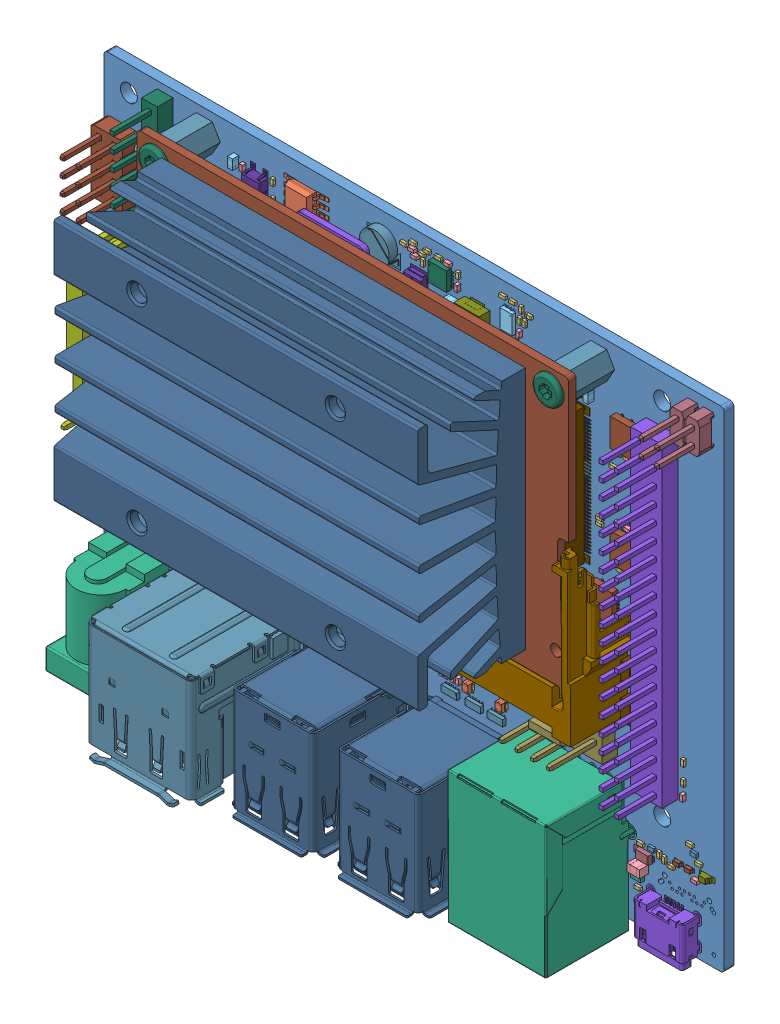
SolidWorks assembly Jetson nano_fixed, configuration Default. Lengths in mm.
Overall size (100 81.03 30.51).
401 component instances, 70 part files, 0 mates.
Components (placement in the parent):
- Jetson nano_fixed.step-1: Jetson nano_fixed.step [Default] at origin size (100 81.03 30.51)
  - 142-13449-1000-A02_ASM.step-1: 142-13449-1000-A02_ASM.step [Default] at origin size (100 81.03 23.19)
    - 142-13449-1000-A02.step-1: 142-13449-1000-A02.step [Default] at origin size (100 79 1.57)
    - 315-1109-000_1.step-1: 315-1109-000_1.step [Default] at (5.6 4.9 1.575) x (-1 0 0) z (0 0 1) size (4.5 3.5 0.8)
    - 0402_H040.step-1: 0402_H040.step [Default] at (8 -0.825 1.575) size (1 0.5 0.4)
    - 0402_H060.step-1: 0402_H060.step [Default] at (1 5 1.575) x (0 -1 0) z (0 0 1) size (1 0.5 0.6)
    - 0402_H040.step-2: 0402_H040.step [Default] at (9.9 -0.3 1.575) size (1 0.5 0.4)
    - 0402_H040.step-3: 0402_H040.step [Default] at (8.296 51.194 1.575) x (-1 0 0) z (0 0 1) size (1 0.5 0.4)
    - 0402_H040.step-4: 0402_H040.step [Default] at (76.2 36.9 1.575) x (-1 0 0) z (0 0 1) size (1 0.5 0.4)
    - 0402_H040.step-5: 0402_H040.step [Default] at (37.8 2.87 1.575) x (0 -1 0) z (0 0 1) size (1 0.5 0.4)
    - 0402_H040.step-6: 0402_H040.step [Default] at (38.6 2.87 1.575) x (0 -1 0) z (0 0 1) size (1 0.5 0.4)
    - 0402_H060.step-2: 0402_H060.step [Default] at (14.2 7.7 1.575) x (0 -1 0) z (0 0 1) size (1 0.5 0.6)
    - 0402_H040.step-7: 0402_H040.step [Default] at (64 27.5 1.575) x (-1 0 0) z (0 0 1) size (1 0.5 0.4)
    - 0402_H060.step-3: 0402_H060.step [Default] at (18.6 43.15 1.575) x (-1 0 0) z (0 0 1) size (1 0.5 0.6)
    - 0402_H060.step-4: 0402_H060.step [Default] at (65.5 52.8 1.575) x (0 1 0) z (0 0 1) size (1 0.5 0.6)
    - 0402_H060.step-5: 0402_H060.step [Default] at (64 28.4 1.575) x (-1 0 0) z (0 0 1) size (1 0.5 0.6)
    - 0402_H040.step-8: 0402_H040.step [Default] at (60.95 25.85 1.575) size (1 0.5 0.4)
    - 0402_H060.step-6: 0402_H060.step [Default] at (17.3 7.7 1.575) x (0 -1 0) z (0 0 1) size (1 0.5 0.6)
    - 0402_H060.step-7: 0402_H060.step [Default] at (18.6 7.7 1.575) x (0 -1 0) z (0 0 1) size (1 0.5 0.6)
    - 0402_H060.step-8: 0402_H060.step [Default] at (12.9 7.7 1.575) x (0 -1 0) z (0 0 1) size (1 0.5 0.6)
    - 0402_H060.step-9: 0402_H060.step [Default] at (80.9 37.7 1.575) x (-1 0 0) z (0 0 1) size (1 0.5 0.6)
    - 0402_H040.step-9: 0402_H040.step [Default] at (79.5 31.3 1.575) size (1 0.5 0.4)
    - 0402_H040.step-10: 0402_H040.step [Default] at (81 31.3 1.575) x (-1 0 0) z (0 0 1) size (1 0.5 0.4)
    - 0402_H060.step-10: 0402_H060.step [Default] at (79.3 37.7 1.575) size (1 0.5 0.6)
    - 0402_H060.step-11: 0402_H060.step [Default] at (74.8 4.05 1.575) x (-1 0 0) z (0 0 1) size (1 0.5 0.6)
    - 0402_H040.step-11: 0402_H040.step [Default] at (65.675 6.15 1.575) x (0 -1 0) z (0 0 1) size (1 0.5 0.4)
    - 0402_H060.step-12: 0402_H060.step [Default] at (67.7 6.85 1.575) x (0 1 0) z (0 0 1) size (1 0.5 0.6)
    - 0402_H040.step-12: 0402_H040.step [Default] at (64.475 5.8 1.575) x (-1 0 0) z (0 0 1) size (1 0.5 0.4)
    - 0402_H040.step-13: 0402_H040.step [Default] at (67.725 5.325 1.575) x (0 1 0) z (0 0 1) size (1 0.5 0.4)
    - 0402_H060.step-13: 0402_H060.step [Default] at (46.1 59.45 1.575) size (1 0.5 0.6)
    - 0402_H040.step-14: 0402_H040.step [Default] at (44.65 59.45 1.575) size (1 0.5 0.4)
    - 0402_H040.step-15: 0402_H040.step [Default] at (46.1 60.25 1.575) size (1 0.5 0.4)
    - 0402_H060.step-14: 0402_H060.step [Default] at (53.35 57.7 1.575) x (0 -1 0) z (0 0 1) size (1 0.5 0.6)
    - 0402_H040.step-16: 0402_H040.step [Default] at (47.6 59.45 1.575) size (1 0.5 0.4)
    - 0402_H040.step-17: 0402_H040.step [Default] at (48.4 60.25 1.575) size (1 0.5 0.4)
    - 0402_H040.step-18: 0402_H040.step [Default] at (47.7 58.325 1.575) x (0 1 0) z (0 0 1) size (1 0.5 0.4)
    - 0402_H060.step-15: 0402_H060.step [Default] at (46.5 58.65 1.575) x (-1 0 0) z (0 0 1) size (1 0.5 0.6)
    - 0402_H060.step-16: 0402_H060.step [Default] at (51.8 60.25 1.575) size (1 0.5 0.6)
    - 0402_H040.step-19: 0402_H040.step [Default] at (53.35 59.4 1.575) x (0 -1 0) z (0 0 1) size (1 0.5 0.4)
    - 0402_H040.step-20: 0402_H040.step [Default] at (50.2 60.25 1.575) x (-1 0 0) z (0 0 1) size (1 0.5 0.4)
    - 0402_H060.step-17: 0402_H060.step [Default] at (18.6 43.95 1.575) x (-1 0 0) z (0 0 1) size (1 0.5 0.6)
    - 0402_H060.step-18: 0402_H060.step [Default] at (52.75 2.9 1.575) x (0 -1 0) z (0 0 1) size (1 0.5 0.6)
    - 0402_H060.step-19: 0402_H060.step [Default] at (22.35 47.4 1.575) x (-1 0 0) z (0 0 1) size (1 0.5 0.6)
    - 0402_H060.step-20: 0402_H060.step [Default] at (20.55 47.4 1.575) x (-1 0 0) z (0 0 1) size (1 0.5 0.6)
    - 0402_H060.step-21: 0402_H060.step [Default] at (21.95 34.55 1.575) x (0 -1 0) z (0 0 1) size (1 0.5 0.6)
    - 0402_H060.step-22: 0402_H060.step [Default] at (21.05 34.55 1.575) x (0 -1 0) z (0 0 1) size (1 0.5 0.6)
    - 0402_H060.step-23: 0402_H060.step [Default] at (53.55 2.9 1.575) x (0 -1 0) z (0 0 1) size (1 0.5 0.6)
    - 0402_H060.step-24: 0402_H060.step [Default] at (25.4 54 1.575) x (-1 0 0) z (0 0 1) size (1 0.5 0.6)
    - 0402_H060.step-25: 0402_H060.step [Default] at (24 34.58 1.575) x (0 -1 0) z (0 0 1) size (1 0.5 0.6)
    - 0402_H040.step-21: 0402_H040.step [Default] at (55.6 2.95 1.575) x (0 -1 0) z (0 0 1) size (1 0.5 0.4)
    - 0402_H040.step-22: 0402_H040.step [Default] at (20.13 34.53 1.575) x (0 1 0) z (0 0 1) size (1 0.5 0.4)
    - 0402_H060.step-26: 0402_H060.step [Default] at (18.4 35.15 1.575) x (0 1 0) z (0 0 1) size (1 0.5 0.6)
    - 0402_H060.step-27: 0402_H060.step [Default] at (18.4 36.75 1.575) x (0 1 0) z (0 0 1) size (1 0.5 0.6)
    - 0402_H040.step-23: 0402_H040.step [Default] at (39.6 2.87 1.575) x (0 -1 0) z (0 0 1) size (1 0.5 0.4)
    - 0402_H040.step-24: 0402_H040.step [Default] at (40.4 2.87 1.575) x (0 -1 0) z (0 0 1) size (1 0.5 0.4)
    - 0402_H040.step-25: 0402_H040.step [Default] at (60.95 2.95 1.575) x (0 -1 0) z (0 0 1) size (1 0.5 0.4)
    - 0402_H040.step-26: 0402_H040.step [Default] at (60.15 2.95 1.575) x (0 -1 0) z (0 0 1) size (1 0.5 0.4)
    - 0402_H040.step-27: 0402_H040.step [Default] at (54.8 2.95 1.575) x (0 -1 0) z (0 0 1) size (1 0.5 0.4)
    - 0402_H040.step-28: 0402_H040.step [Default] at (31.6 54 1.575) size (1 0.5 0.4)
    - 0402_H040.step-29: 0402_H040.step [Default] at (27.4 54 1.575) size (1 0.5 0.4)
    - 0402_H040.step-30: 0402_H040.step [Default] at (29.6 54 1.575) x (-1 0 0) z (0 0 1) size (1 0.5 0.4)
    - 0402_H040.step-31: 0402_H040.step [Default] at (63.775 -14.475 1.575) size (1 0.5 0.4)
    - 0402_H040.step-32: 0402_H040.step [Default] at (63.775 -15.275 1.575) size (1 0.5 0.4)
    - 0402_H040.step-33: 0402_H040.step [Default] at (8.025 41.475 1.575) x (-1 0 0) z (0 0 1) size (1 0.5 0.4)
    - 0402_H060.step-28: 0402_H060.step [Default] at (63.95 1.25 1.575) x (0 1 0) z (0 0 1) size (1 0.5 0.6)
    - 0402_H060.step-29: 0402_H060.step [Default] at (2.95 54.05 1.575) x (0 1 0) z (0 0 1) size (1 0.5 0.6)
    - 0402_H040.step-34: 0402_H040.step [Default] at (92.2 -3.45 1.575) x (-1 0 0) z (0 0 1) size (1 0.5 0.4)
    - 0402_H060.step-30: 0402_H060.step [Default] at (32.85 7.7 1.575) x (0 -1 0) z (0 0 1) size (1 0.5 0.6)
    - 0402_H060.step-31: 0402_H060.step [Default] at (27.25 7.7 1.575) x (0 -1 0) z (0 0 1) size (1 0.5 0.6)
    - 0402_H060.step-32: 0402_H060.step [Default] at (31.25 7.7 1.575) x (0 -1 0) z (0 0 1) size (1 0.5 0.6)
    - 0402_H060.step-33: 0402_H060.step [Default] at (28.85 7.7 1.575) x (0 -1 0) z (0 0 1) size (1 0.5 0.6)
    - 0402_H060.step-34: 0402_H060.step [Default] at (32.05 7.7 1.575) x (0 -1 0) z (0 0 1) size (1 0.5 0.6)
    - 0402_H060.step-35: 0402_H060.step [Default] at (28.05 7.7 1.575) x (0 -1 0) z (0 0 1) size (1 0.5 0.6)
    - 0402_H060.step-36: 0402_H060.step [Default] at (30.45 7.7 1.575) x (0 -1 0) z (0 0 1) size (1 0.5 0.6)
    - 0402_H060.step-37: 0402_H060.step [Default] at (29.65 7.7 1.575) x (0 -1 0) z (0 0 1) size (1 0.5 0.6)
    - 0402_H060.step-38: 0402_H060.step [Default] at (24.65 6.41 1.575) x (0 -1 0) z (0 0 1) size (1 0.5 0.6)
    - 0402_H060.step-39: 0402_H060.step [Default] at (25.85 6.41 1.575) x (0 -1 0) z (0 0 1) size (1 0.5 0.6)
    - 0402_H060.step-40: 0402_H060.step [Default] at (4.2 36.5 1.575) x (0 1 0) z (0 0 1) size (1 0.5 0.6)
    - 0402_H060.step-41: 0402_H060.step [Default] at (89.7 4.7 1.575) x (0 -1 0) z (0 0 1) size (1 0.5 0.6)
    - 0402_H060.step-42: 0402_H060.step [Default] at (82.5 3.8 1.575) x (0 -1 0) z (0 0 1) size (1 0.5 0.6)
    - 0402_H060.step-43: 0402_H060.step [Default] at (12.65 49.7 1.575) size (1 0.5 0.6)
    - 0402_H060.step-44: 0402_H060.step [Default] at (11.2 50.15 1.575) x (0 -1 0) z (0 0 1) size (1 0.5 0.6)
    - 0402_H060.step-45: 0402_H060.step [Default] at (26.5 34.55 1.575) x (0 -1 0) z (0 0 1) size (1 0.5 0.6)
    - 0402_H060.step-46: 0402_H060.step [Default] at (29.9 34.5 1.575) x (0 -1 0) z (0 0 1) size (1 0.5 0.6)
    - 0402_H060.step-47: 0402_H060.step [Default] at (31.7 40.15 1.575) x (0 1 0) z (0 0 1) size (1 0.5 0.6)
    - 0402_H060.step-48: 0402_H060.step [Default] at (31.15 42.5 1.575) x (0 1 0) z (0 0 1) size (1 0.5 0.6)
    - 0402_H060.step-49: 0402_H060.step [Default] at (19.2 47.05 1.575) x (0 1 0) z (0 0 1) size (1 0.5 0.6)
    - 0402_H060.step-50: 0402_H060.step [Default] at (17.95 42 1.575) x (0 -1 0) z (0 0 1) size (1 0.5 0.6)
    - 0402_H060.step-51: 0402_H060.step [Default] at (27.3 48.25 1.575) x (0 1 0) z (0 0 1) size (1 0.5 0.6)
    - 0402_H060.step-52: 0402_H060.step [Default] at (31.7 37.85 1.575) x (0 -1 0) z (0 0 1) size (1 0.5 0.6)
    - 0402_H060.step-53: 0402_H060.step [Default] at (29.6 48.35 1.575) x (0 1 0) z (0 0 1) size (1 0.5 0.6)
    - 0402_H060.step-54: 0402_H060.step [Default] at (18.8 38.75 1.575) x (-1 0 0) z (0 0 1) size (1 0.5 0.6)
    - 0402_H060.step-55: 0402_H060.step [Default] at (18.7 57.2 1.575) x (0 -1 0) z (0 0 1) size (1 0.5 0.6)
    - 0402_H060.step-56: 0402_H060.step [Default] at (34.1 2.9 1.575) x (0 -1 0) z (0 0 1) size (1 0.5 0.6)
    - 0402_H060.step-57: 0402_H060.step [Default] at (35.8 2.9 1.575) x (0 -1 0) z (0 0 1) size (1 0.5 0.6)
    - 0402_H060.step-58: 0402_H060.step [Default] at (34.9 2.9 1.575) x (0 -1 0) z (0 0 1) size (1 0.5 0.6)
    - 0402_H060.step-59: 0402_H060.step [Default] at (36.6 2.9 1.575) x (0 -1 0) z (0 0 1) size (1 0.5 0.6)
    - 0402_H060.step-60: 0402_H060.step [Default] at (11.325 44.725 1.575) size (1 0.5 0.6)
    - 0402_H060.step-61: 0402_H060.step [Default] at (50.95 2.9 1.575) x (0 -1 0) z (0 0 1) size (1 0.5 0.6)
    - 0402_H060.step-62: 0402_H060.step [Default] at (51.75 2.9 1.575) x (0 -1 0) z (0 0 1) size (1 0.5 0.6)
    - 0402_H060.step-63: 0402_H060.step [Default] at (11.55 39.7 1.575) size (1 0.5 0.6)
    - 0402_H060.step-64: 0402_H060.step [Default] at (9.5 -8.5 1.575) x (-1 0 0) z (0 0 1) size (1 0.5 0.6)
    - 0402_H060.step-65: 0402_H060.step [Default] at (61.35 38.05 1.575) x (0 -1 0) z (0 0 1) size (1 0.5 0.6)
    - 0402_H060.step-66: 0402_H060.step [Default] at (60.55 38.05 1.575) x (0 -1 0) z (0 0 1) size (1 0.5 0.6)
    - 0402_H060.step-67: 0402_H060.step [Default] at (29.3 25.65 1.575) x (0 -1 0) z (0 0 1) size (1 0.5 0.6)
    - 0402_H060.step-68: 0402_H060.step [Default] at (63.3 56.2 1.575) x (0 1 0) z (0 0 1) size (1 0.5 0.6)
    - 0402_H060.step-69: 0402_H060.step [Default] at (20.5 54.2 1.575) size (1 0.5 0.6)
    - 0402_H060.step-70: 0402_H060.step [Default] at (60.1 32.15 1.575) x (0 1 0) z (0 0 1) size (1 0.5 0.6)
    - 0402_H060.step-71: 0402_H060.step [Default] at (60.9 32.15 1.575) x (0 1 0) z (0 0 1) size (1 0.5 0.6)
    - 0402_H060.step-72: 0402_H060.step [Default] at (18.6 44.85 1.575) size (1 0.5 0.6)
    - 0402_H060.step-73: 0402_H060.step [Default] at (18.6 45.65 1.575) size (1 0.5 0.6)
    - 0402_H060.step-74: 0402_H060.step [Default] at (18.1 27.25 1.575) size (1 0.5 0.6)
    - 0402_H060.step-75: 0402_H060.step [Default] at (15.1 7.7 1.575) x (0 -1 0) z (0 0 1) size (1 0.5 0.6)
    - 0402_H060.step-76: 0402_H060.step [Default] at (16.4 7.7 1.575) x (0 -1 0) z (0 0 1) size (1 0.5 0.6)
    - 0402_H060.step-77: 0402_H060.step [Default] at (20.8 7.7 1.575) x (0 -1 0) z (0 0 1) size (1 0.5 0.6)
    - 0402_H060.step-78: 0402_H060.step [Default] at (19.5 7.7 1.575) x (0 -1 0) z (0 0 1) size (1 0.5 0.6)
    - 0402_H060.step-79: 0402_H060.step [Default] at (21.9 2.8 1.575) size (1 0.5 0.6)
    - 0402_H060.step-80: 0402_H060.step [Default] at (12.75 29 1.575) size (1 0.5 0.6)
    - 0402_H060.step-81: 0402_H060.step [Default] at (10.225 5.1 1.575) size (1 0.5 0.6)
    - 0402_H060.step-82: 0402_H060.step [Default] at (22.8 27.65 1.575) x (0 1 0) z (0 0 1) size (1 0.5 0.6)
    - 0402_H060.step-83: 0402_H060.step [Default] at (18.85 25.15 1.575) x (0 -1 0) z (0 0 1) size (1 0.5 0.6)
    - 0402_H060.step-84: 0402_H060.step [Default] at (17.95 40.1 1.575) x (0 1 0) z (0 0 1) size (1 0.5 0.6)
    - 0402_H040.step-35: 0402_H040.step [Default] at (20.8 6.2 1.575) x (0 1 0) z (0 0 1) size (1 0.5 0.4)
    - 0402_H040.step-36: 0402_H040.step [Default] at (76 22.7 1.575) size (1 0.5 0.4)
    - 0402_H040.step-37: 0402_H040.step [Default] at (23.7 26.85 1.575) x (0 1 0) z (0 0 1) size (1 0.5 0.4)
    - 0402_H040.step-38: 0402_H040.step [Default] at (18 25.15 1.575) x (0 1 0) z (0 0 1) size (1 0.5 0.4)
    - 0402_H040.step-39: 0402_H040.step [Default] at (17.3 28.25 1.575) x (-1 0 0) z (0 0 1) size (1 0.5 0.4)
    - 0402_H040.step-40: 0402_H040.step [Default] at (13.15 4.2 1.575) x (0 -1 0) z (0 0 1) size (1 0.5 0.4)
    - 0402_H040.step-41: 0402_H040.step [Default] at (17.2 30.15 1.575) x (0 -1 0) z (0 0 1) size (1 0.5 0.4)
    - 0402_H040.step-42: 0402_H040.step [Default] at (14.2 6.2 1.575) x (0 1 0) z (0 0 1) size (1 0.5 0.4)
    - 0402_H040.step-43: 0402_H040.step [Default] at (12.9 6.2 1.575) x (0 1 0) z (0 0 1) size (1 0.5 0.4)
    - 0402_H040.step-44: 0402_H040.step [Default] at (15.1 6.2 1.575) x (0 1 0) z (0 0 1) size (1 0.5 0.4)
    - 0402_H040.step-45: 0402_H040.step [Default] at (16.4 6.2 1.575) x (0 1 0) z (0 0 1) size (1 0.5 0.4)
    - 0402_H040.step-46: 0402_H040.step [Default] at (19.5 6.2 1.575) x (0 1 0) z (0 0 1) size (1 0.5 0.4)
    - 0402_H040.step-47: 0402_H040.step [Default] at (17.3 6.2 1.575) x (0 1 0) z (0 0 1) size (1 0.5 0.4)
    - 0402_H040.step-48: 0402_H040.step [Default] at (18.6 6.2 1.575) x (0 1 0) z (0 0 1) size (1 0.5 0.4)
    - 0402_H040.step-49: 0402_H040.step [Default] at (24.2 24.55 1.575) x (0 1 0) z (0 0 1) size (1 0.5 0.4)
    - 0402_H040.step-50: 0402_H040.step [Default] at (23.5 54.9 1.575) x (0 1 0) z (0 0 1) size (1 0.5 0.4)
    - 0402_H040.step-51: 0402_H040.step [Default] at (13.2 39.75 1.575) x (-1 0 0) z (0 0 1) size (1 0.5 0.4)
    - 0402_H040.step-52: 0402_H040.step [Default] at (80.7 47.4 1.575) x (-1 0 0) z (0 0 1) size (1 0.5 0.4)
    - 0402_H040.step-53: 0402_H040.step [Default] at (77.5 22.7 1.575) x (-1 0 0) z (0 0 1) size (1 0.5 0.4)
    - 0402_H040.step-54: 0402_H040.step [Default] at (9.25 -12.75 1.575) x (-1 0 0) z (0 0 1) size (1 0.5 0.4)
    - 0402_H040.step-55: 0402_H040.step [Default] at (9.25 -11.95 1.575) x (-1 0 0) z (0 0 1) size (1 0.5 0.4)
    - 0402_H040.step-56: 0402_H040.step [Default] at (64.475 6.7 1.575) size (1 0.5 0.4)
    - 0402_H040.step-57: 0402_H040.step [Default] at (29.3 24 1.575) x (0 1 0) z (0 0 1) size (1 0.5 0.4)
    - 0402_H040.step-58: 0402_H040.step [Default] at (64.2 32.5 1.575) x (0 1 0) z (0 0 1) size (1 0.5 0.4)
    - 0402_H040.step-59: 0402_H040.step [Default] at (64.15 47.45 1.575) x (0 -1 0) z (0 0 1) size (1 0.5 0.4)
    - 0402_H040.step-60: 0402_H040.step [Default] at (64.2 31 1.575) x (0 -1 0) z (0 0 1) size (1 0.5 0.4)
    - 0402_H040.step-61: 0402_H040.step [Default] at (76.2 36.1 1.575) x (-1 0 0) z (0 0 1) size (1 0.5 0.4)
    - 0402_H040.step-62: 0402_H040.step [Default] at (78.4 45.15 1.575) size (1 0.5 0.4)
    - 0402_H040.step-63: 0402_H040.step [Default] at (81.7 38.6 1.575) size (1 0.5 0.4)
    - 0402_H040.step-64: 0402_H040.step [Default] at (81.7 39.4 1.575) size (1 0.5 0.4)
    - 0402_H040.step-65: 0402_H040.step [Default] at (59.35 51.825 1.575) size (1 0.5 0.4)
    - 0402_H040.step-66: 0402_H040.step [Default] at (60.825 51.825 1.575) x (-1 0 0) z (0 0 1) size (1 0.5 0.4)
    - 0402_H040.step-67: 0402_H040.step [Default] at (89.7 9.5 1.575) x (0 1 0) z (0 0 1) size (1 0.5 0.4)
    - 0402_H040.step-68: 0402_H040.step [Default] at (89.7 6.7 1.575) x (0 1 0) z (0 0 1) size (1 0.5 0.4)
    - 0402_H040.step-69: 0402_H040.step [Default] at (3.9 34.2 1.575) x (0 -1 0) z (0 0 1) size (1 0.5 0.4)
    - 0402_H040.step-70: 0402_H040.step [Default] at (5.1 35 1.575) x (0 1 0) z (0 0 1) size (1 0.5 0.4)
    - 0402_H040.step-71: 0402_H040.step [Default] at (32.85 5.81 1.575) x (0 -1 0) z (0 0 1) size (1 0.5 0.4)
    - 0402_H040.step-72: 0402_H040.step [Default] at (32.05 5.81 1.575) x (0 -1 0) z (0 0 1) size (1 0.5 0.4)
    - 0402_H040.step-73: 0402_H040.step [Default] at (27.25 5.81 1.575) x (0 -1 0) z (0 0 1) size (1 0.5 0.4)
    - 0402_H040.step-74: 0402_H040.step [Default] at (28.05 5.81 1.575) x (0 -1 0) z (0 0 1) size (1 0.5 0.4)
    - 0402_H040.step-75: 0402_H040.step [Default] at (31.25 5.81 1.575) x (0 -1 0) z (0 0 1) size (1 0.5 0.4)
    - 0402_H040.step-76: 0402_H040.step [Default] at (30.45 5.81 1.575) x (0 -1 0) z (0 0 1) size (1 0.5 0.4)
    - 0402_H040.step-77: 0402_H040.step [Default] at (28.85 5.81 1.575) x (0 -1 0) z (0 0 1) size (1 0.5 0.4)
    - 0402_H040.step-78: 0402_H040.step [Default] at (29.65 5.81 1.575) x (0 -1 0) z (0 0 1) size (1 0.5 0.4)
    - 0402_H040.step-79: 0402_H040.step [Default] at (13.5 52.9 1.575) x (-1 0 0) z (0 0 1) size (1 0.5 0.4)
    - 0402_H040.step-80: 0402_H040.step [Default] at (22.35 4 1.575) x (0 -1 0) z (0 0 1) size (1 0.5 0.4)
    - 0402_H040.step-81: 0402_H040.step [Default] at (21.55 4 1.575) x (0 1 0) z (0 0 1) size (1 0.5 0.4)
    - 0402_H040.step-82: 0402_H040.step [Default] at (25.85 4.9 1.575) x (0 -1 0) z (0 0 1) size (1 0.5 0.4)
    - 0402_H040.step-83: 0402_H040.step [Default] at (11.8 52.9 1.575) size (1 0.5 0.4)
    - 0402_H040.step-84: 0402_H040.step [Default] at (9.432 51.594 1.575) x (0 -1 0) z (0 0 1) size (1 0.5 0.4)
    - 0402_H040.step-85: 0402_H040.step [Default] at (8.975 50.3 1.575) size (1 0.5 0.4)
    - 0402_H040.step-86: 0402_H040.step [Default] at (82.8 -5.3 1.575) x (-1 0 0) z (0 0 1) size (1 0.5 0.4)
    - 0402_H040.step-87: 0402_H040.step [Default] at (82.4 -11.6 1.575) x (-1 0 0) z (0 0 1) size (1 0.5 0.4)
    - 0402_H040.step-88: 0402_H040.step [Default] at (22.8 26.05 1.575) x (0 1 0) z (0 0 1) size (1 0.5 0.4)
    - 0402_H040.step-89: 0402_H040.step [Default] at (20.8 28.25 1.575) size (1 0.5 0.4)
    - 0402_H040.step-90: 0402_H040.step [Default] at (20.8 24.65 1.575) x (-1 0 0) z (0 0 1) size (1 0.5 0.4)
    - 0402_H040.step-91: 0402_H040.step [Default] at (18.1 26.45 1.575) size (1 0.5 0.4)
    - 0402_H040.step-92: 0402_H040.step [Default] at (24.65 8.41 1.575) x (0 1 0) z (0 0 1) size (1 0.5 0.4)
    - 0402_H040.step-93: 0402_H040.step [Default] at (25.85 8.41 1.575) x (0 1 0) z (0 0 1) size (1 0.5 0.4)
    - 0402_H040.step-94: 0402_H040.step [Default] at (3.8 54.4 1.575) x (0 -1 0) z (0 0 1) size (1 0.5 0.4)
    - 0402_H040.step-95: 0402_H040.step [Default] at (2.45 44.45 1.575) x (0 -1 0) z (0 0 1) size (1 0.5 0.4)
    - 0402_H040.step-96: 0402_H040.step [Default] at (24.65 4.9 1.575) x (0 1 0) z (0 0 1) size (1 0.5 0.4)
    - 0402_H040.step-97: 0402_H040.step [Default] at (22.15 7.6 1.575) x (-1 0 0) z (0 0 1) size (1 0.5 0.4)
    - 0402_H040.step-98: 0402_H040.step [Default] at (79.2 47.4 1.575) size (1 0.5 0.4)
    - 0402_H040.step-99: 0402_H040.step [Default] at (19 28.25 1.575) size (1 0.5 0.4)
    - 0402_H040.step-100: 0402_H040.step [Default] at (9.65 9.7 1.575) x (0 -1 0) z (0 0 1) size (1 0.5 0.4)
    - 0402_H040.step-101: 0402_H040.step [Default] at (28.35 34.45 1.575) x (0 1 0) z (0 0 1) size (1 0.5 0.4)
    - 0402_H040.step-102: 0402_H040.step [Default] at (25.2 34.55 1.575) x (0 1 0) z (0 0 1) size (1 0.5 0.4)
    - 0402_H040.step-103: 0402_H040.step [Default] at (10.625 6.35 1.575) x (0 -1 0) z (0 0 1) size (1 0.5 0.4)
    - 0402_H040.step-104: 0402_H040.step [Default] at (9.825 6.35 1.575) x (0 1 0) z (0 0 1) size (1 0.5 0.4)
    - 0402_H040.step-105: 0402_H040.step [Default] at (4.775 42.975 1.575) x (0 1 0) z (0 0 1) size (1 0.5 0.4)
    - 0402_H040.step-106: 0402_H040.step [Default] at (19.8 32.9 1.575) x (-1 0 0) z (0 0 1) size (1 0.5 0.4)
    - 0402_H040.step-107: 0402_H040.step [Default] at (22.35 24.65 1.575) x (-1 0 0) z (0 0 1) size (1 0.5 0.4)
    - 0402_H040.step-108: 0402_H040.step [Default] at (62.4 54.7 1.575) size (1 0.5 0.4)
    - 0402_H040.step-109: 0402_H040.step [Default] at (62.2 60.05 1.575) x (-1 0 0) z (0 0 1) size (1 0.5 0.4)
    - 0402_H040.step-110: 0402_H040.step [Default] at (23.5 57.5 1.575) x (0 1 0) z (0 0 1) size (1 0.5 0.4)
    - 0402_H040.step-111: 0402_H040.step [Default] at (12.8 44.725 1.575) size (1 0.5 0.4)
    - 0402_H040.step-112: 0402_H040.step [Default] at (21.8 31.45 1.575) x (0 1 0) z (0 0 1) size (1 0.5 0.4)
    - 0402_H040.step-113: 0402_H040.step [Default] at (19.25 34.55 1.575) x (0 1 0) z (0 0 1) size (1 0.5 0.4)
    - 0402_H040.step-114: 0402_H040.step [Default] at (0.95 41.55 1.575) size (1 0.5 0.4)
    - 0402_H040.step-115: 0402_H040.step [Default] at (64.1 58 1.575) x (0 1 0) z (0 0 1) size (1 0.5 0.4)
    - 0402_H040.step-116: 0402_H040.step [Default] at (63.3 58 1.575) x (0 -1 0) z (0 0 1) size (1 0.5 0.4)
    - 0402_H040.step-117: 0402_H040.step [Default] at (63.55 59.7 1.575) x (0 -1 0) z (0 0 1) size (1 0.5 0.4)
    - 0402_H060.step-85: 0402_H060.step [Default] at (71.175 4 1.575) x (-1 0 0) z (0 0 1) size (1 0.5 0.6)
    - 0402_H040.step-118: 0402_H040.step [Default] at (86.6 -5.6 1.575) x (0 1 0) z (0 0 1) size (1 0.5 0.4)
    - 0402_H040.step-119: 0402_H040.step [Default] at (85.8 -5.3 1.575) x (0 1 0) z (0 0 1) size (1 0.5 0.4)
    - 0402_H040.step-120: 0402_H040.step [Default] at (10.25 51.6 1.575) x (0 1 0) z (0 0 1) size (1 0.5 0.4)
    - 0402_H040.step-121: 0402_H040.step [Default] at (80.5 28.55 1.575) size (1 0.5 0.4)
    - 0402_H040.step-122: 0402_H040.step [Default] at (13.95 4.2 1.575) x (0 -1 0) z (0 0 1) size (1 0.5 0.4)
    - 0402_H040.step-123: 0402_H040.step [Default] at (15.35 4.2 1.575) x (0 -1 0) z (0 0 1) size (1 0.5 0.4)
    - 0402_H040.step-124: 0402_H040.step [Default] at (16.15 4.2 1.575) x (0 -1 0) z (0 0 1) size (1 0.5 0.4)
    - 0402_H040.step-125: 0402_H040.step [Default] at (20.55 4.2 1.575) x (0 -1 0) z (0 0 1) size (1 0.5 0.4)
    - 0402_H040.step-126: 0402_H040.step [Default] at (19.75 4.2 1.575) x (0 -1 0) z (0 0 1) size (1 0.5 0.4)
    - 0402_H040.step-127: 0402_H040.step [Default] at (17.6 4.2 1.575) x (0 -1 0) z (0 0 1) size (1 0.5 0.4)
    - 0402_H040.step-128: 0402_H040.step [Default] at (18.4 4.2 1.575) x (0 -1 0) z (0 0 1) size (1 0.5 0.4)
    - 0402_H060.step-86: 0402_H060.step [Default] at (64.25 -13.325 1.575) x (0 -1 0) z (0 0 1) size (1 0.5 0.6)
    - 0402_H060.step-87: 0402_H060.step [Default] at (64.225 -11.825 1.575) x (0 1 0) z (0 0 1) size (1 0.5 0.6)
    - 0402_H040.step-129: 0402_H040.step [Default] at (63.8 -6.85 1.575) x (0 1 0) z (0 0 1) size (1 0.5 0.4)
    - 0402_H040.step-130: 0402_H040.step [Default] at (81.7 41.95 1.575) size (1 0.5 0.4)
    - 0402_H040.step-131: 0402_H040.step [Default] at (87.75 -6 1.575) x (-1 0 0) z (0 0 1) size (1 0.5 0.4)
    - 0402_H040.step-132: 0402_H040.step [Default] at (82.4 -13.6 1.575) x (-1 0 0) z (0 0 1) size (1 0.5 0.4)
    - 0402_H060.step-88: 0402_H060.step [Default] at (91.75 -5.95 1.575) size (1 0.5 0.6)
    - 0402_H040.step-133: 0402_H040.step [Default] at (3.65 49.25 1.575) x (0 -1 0) z (0 0 1) size (1 0.5 0.4)
    - 0402_H040.step-134: 0402_H040.step [Default] at (2.45 49.25 1.575) x (0 1 0) z (0 0 1) size (1 0.5 0.4)
    - 0402_H040.step-135: 0402_H040.step [Default] at (90.75 -1.45 1.575) x (-1 0 0) z (0 0 1) size (1 0.5 0.4)
    - 0402_H040.step-136: 0402_H040.step [Default] at (8.45 39.55 1.575) x (0 -1 0) z (0 0 1) size (1 0.5 0.4)
    - 0402_H060.step-89: 0402_H060.step [Default] at (8.85 -5.25 1.575) x (-1 0 0) z (0 0 1) size (1 0.5 0.6)
    - 0402_H040.step-137: 0402_H040.step [Default] at (18.6 32.55 1.575) x (0 1 0) z (0 0 1) size (1 0.5 0.4)
    - 0402_H060.step-90: 0402_H060.step [Default] at (4.5 44.45 1.575) x (0 1 0) z (0 0 1) size (1 0.5 0.6)
    - 0402_H040.step-138: 0402_H040.step [Default] at (8.35 2.75 1.575) size (1 0.5 0.4)
    - 0402_H040.step-139: 0402_H040.step [Default] at (9.4 1.95 1.575) size (1 0.5 0.4)
    - 0402_H040.step-140: 0402_H040.step [Default] at (8.2 1.55 1.575) x (0 1 0) z (0 0 1) size (1 0.5 0.4)
    - 0402_H060.step-91: 0402_H060.step [Default] at (8.5 3.875 1.575) x (0 -1 0) z (0 0 1) size (1 0.5 0.6)
    - 0402_H060.step-92: 0402_H060.step [Default] at (-0.8 41.5 1.575) x (-1 0 0) z (0 0 1) size (1 0.5 0.6)
    - 0402_H040.step-141: 0402_H040.step [Default] at (-1.35 7.75 1.575) size (1 0.5 0.4)
    - 0402_H040.step-142: 0402_H040.step [Default] at (8 0.425 1.575) size (1 0.5 0.4)
    - 0402_H040.step-143: 0402_H040.step [Default] at (67.9 4.025 1.575) x (-1 0 0) z (0 0 1) size (1 0.5 0.4)
    - 0402_H040.step-144: 0402_H040.step [Default] at (60.6 60.05 1.575) x (-1 0 0) z (0 0 1) size (1 0.5 0.4)
    - 0402_H040.step-145: 0402_H040.step [Default] at (72.85 4 1.575) x (-1 0 0) z (0 0 1) size (1 0.5 0.4)
    - 0402_H040.step-146: 0402_H040.step [Default] at (64.8 59.35 1.575) size (1 0.5 0.4)
    - 0402_H040.step-147: 0402_H040.step [Default] at (7.2 7.3 1.575) size (1 0.5 0.4)
    - 0402_H040.step-148: 0402_H040.step [Default] at (8.5 5.35 1.575) x (0 1 0) z (0 0 1) size (1 0.5 0.4)
    - 0402_H040.step-149: 0402_H040.step [Default] at (8.475 7.075 1.575) x (0 1 0) z (0 0 1) size (1 0.5 0.4)
    - VIRTUAL_SHORT.step-1: VIRTUAL_SHORT.step [Default] at (23.5 32.9 1.575) x (0 1 0) z (0 0 1) size (0.25 0.25 1)
    - VIRTUAL_SHORT.step-2: VIRTUAL_SHORT.step [Default] at (26.85 32.85 1.575) x (0 1 0) z (0 0 1) size (0.25 0.25 1)
    - VIRTUAL_SHORT.step-3: VIRTUAL_SHORT.step [Default] at (30.6 33.8 1.575) x (0 1 0) z (0 0 1) size (0.25 0.25 1)
    - VIRTUAL_SHORT.step-4: VIRTUAL_SHORT.step [Default] at (32.65 39.75 1.575) x (-1 0 0) z (0 0 1) size (0.25 0.25 1)
    - VIRTUAL_SHORT.step-5: VIRTUAL_SHORT.step [Default] at (31.85 42.1 1.575) x (-1 0 0) z (0 0 1) size (0.25 0.25 1)
    - VIRTUAL_SHORT.step-6: VIRTUAL_SHORT.step [Default] at (17.35 42.4 1.575) size (0.25 0.25 1)
    - VIRTUAL_SHORT.step-7: VIRTUAL_SHORT.step [Default] at (18.6 46.6 1.575) size (0.25 0.25 1)
    - VIRTUAL_SHORT.step-8: VIRTUAL_SHORT.step [Default] at (20.9 32.9 1.575) x (0 1 0) z (0 0 1) size (0.25 0.25 1)
    - VIRTUAL_SHORT.step-9: VIRTUAL_SHORT.step [Default] at (28.6 48.25 1.575) x (0 -1 0) z (0 0 1) size (0.25 0.25 1)
    - VIRTUAL_SHORT.step-10: VIRTUAL_SHORT.step [Default] at (27.1 49.35 1.575) x (0 -1 0) z (0 0 1) size (0.25 0.25 1)
    - VIRTUAL_SHORT.step-11: VIRTUAL_SHORT.step [Default] at (22.1 32.95 1.575) x (-1 0 0) z (0 0 1) size (0.25 0.25 1)
    - VIRTUAL_SHORT.step-12: VIRTUAL_SHORT.step [Default] at (32.65 38.25 1.575) x (-1 0 0) z (0 0 1) size (0.25 0.25 1)
    - VIRTUAL_SHORT.step-13: VIRTUAL_SHORT.step [Default] at (30.3 48 1.575) x (-1 0 0) z (0 0 1) size (0.25 0.25 1)
    - VIRTUAL_SHORT.step-14: VIRTUAL_SHORT.step [Default] at (17.15 38.95 1.575) size (0.25 0.25 1)
    - VIRTUAL_SHORT.step-15: VIRTUAL_SHORT.step [Default] at (17.15 39.7 1.575) size (0.25 0.25 1)
    - VIRTUAL_SHORT.step-16: VIRTUAL_SHORT.step [Default] at (76.175 4.1 1.575) x (-1 0 0) z (0 0 1) size (0.25 0.25 1)
    - 064-0377-000_2.step-1: 064-0377-000_2.step [Default] at (2 -4.75 1.575) x (0 -1 0) z (0 0 1) size (14.63 10.08 14.5)
    - 074-0117-000_2.step-1: 074-0117-000_2.step [Default] at (0.254 14.3 1.575) size (5.08 2.54 11.66)
    - 090-0096-000_1.step-1: 090-0096-000_1.step [Default] at (3.45 44.4 1.575) x (0 -1 0) z (0 0 1) size (1.2 0.6 0.4)
    - 090-0309-000_1.step-1: 090-0309-000_1.step [Default] at (-1.65 8.7 1.575) x (-1 0 0) z (0 0 1) size (1.2 0.6 0.4)
    - 115-1232-000_2.step-1: 115-1232-000_2.step [Default] at (1.25 6.5 1.575) x (-1 0 0) z (0 0 1) size (0.9 0.9 0.33)
    - 074-0102-000_4.step-1: 074-0102-000_4.step [Default] at (0.254 44.36 1.575) x (0 1 0) z (0 0 1) size (10.16 5.08 11.6)
    - 064-0400-000_1.step-1: 064-0400-000_1.step [Default] at (73.75 7.77 1.575) size (10.16 5.8 13.5)
    - MEC_STANDOFF_PTH_620C380P.step-1: MEC_STANDOFF_PTH_620C380P.step [Default] at (40.276 40.3 1.575) x (0 1 0) z (0 0 1) size (6.2 6.2 0.73)
    - 090-0231-000_1.step-1: 090-0231-000_1.step [Default] at (35.3 0.7 1.575) x (-1 0 0) z (0 0 1) size (2.5 1.55 0.55)
    - 090-0231-000_1.step-2: 090-0231-000_1.step [Default] at (52.25 0.7 1.575) x (-1 0 0) z (0 0 1) size (2.5 1.55 0.55)
    - 090-0231-000_1.step-3: 090-0231-000_1.step [Default] at (56.05 0.7 1.575) size (2.5 1.55 0.55)
    - 090-0231-000_1.step-4: 090-0231-000_1.step [Default] at (59.65 0.7 1.575) size (2.5 1.55 0.55)
    - 090-0231-000_1.step-5: 090-0231-000_1.step [Default] at (39.1 0.7 1.575) size (2.5 1.55 0.55)
    - 090-0231-000_1.step-6: 090-0231-000_1.step [Default] at (43.1 0.7 1.575) size (2.5 1.55 0.55)
    - 090-0231-000_1.step-7: 090-0231-000_1.step [Default] at (14.6 1.8 1.575) size (2.5 1.55 0.55)
    - 090-0231-000_1.step-8: 090-0231-000_1.step [Default] at (19.1 1.8 1.575) size (2.5 1.55 0.55)
    - 090-0231-000_1.step-9: 090-0231-000_1.step [Default] at (22.5 1.4 1.575) size (2.5 1.55 0.55)
    - 090-0231-000_1.step-10: 090-0231-000_1.step [Default] at (28.45 3.35 1.575) size (2.5 1.55 0.55)
    - 090-0231-000_1.step-11: 090-0231-000_1.step [Default] at (31.65 3.35 1.575) size (2.5 1.55 0.55)
    - 074-0223-000_2.step-1: 074-0223-000_2.step [Default] at (5.85 53.25 1.575) x (0 1 0) z (0 0 1) size (15.24 2.54 11.6)
    - 131-0832-000_2.step-1: 131-0832-000_2.step [Default] at (56.3 54.7 1.575) x (0 -1 0) z (0 0 1) size (4.96 4.06 1.8)
    - 115-0836-000_1.step-1: 115-0836-000_1.step [Default] at (21.1 56.6 1.575) size (2.9 3.58 1.45)
    - 115-0836-000_1.step-2: 115-0836-000_1.step [Default] at (11.8 42.3 1.575) size (2.9 3.58 1.45)
    - 315-0620-000_1.step-1: 315-0620-000_1.step [Default] at (72.1 53.4 1.575) x (0 -1 0) z (0 0 1) size (2.9 3.58 1.1)
    - 315-1062-000_1.step-1: 315-1062-000_1.step [Default] at (26.8 25.15 1.575) x (0 -1 0) z (0 0 1) size (2.9 3.58 1.45)
    - 170-0285-000_1.step-1: 170-0285-000_1.step [Default] at (28.72 57.28 1.575) x (0 1 0) z (0 0 1) size (4.9 7.21 1.75)
    - 115-0138-000_1.step-1: 115-0138-000_1.step [Default] at (9.15 48.55 1.575) x (0 1 0) z (0 0 1) size (2 2.88 1.1)
    - 115-1821-000_1.step-1: 115-1821-000_1.step [Default] at (3.3 40.8 1.575) x (-1 0 0) z (0 0 1) size (2 2.88 1.1)
    - 115-1821-000_1.step-2: 115-1821-000_1.step [Default] at (6.25 39.55 1.575) x (0 -1 0) z (0 0 1) size (2 2.88 1.1)
    - 115-0742-000_2.step-1: 115-0742-000_2.step [Default] at (3.05 46.85 1.575) size (2 2.88 1.1)
    - 115-0742-000_2.step-2: 115-0742-000_2.step [Default] at (3.05 51.65 1.575) x (-1 0 0) z (0 0 1) size (2 2.88 1.1)
    - 115-1821-000_1.step-3: 115-1821-000_1.step [Default] at (59.6 27.6 1.575) x (0 1 0) z (0 0 1) size (2 2.88 1.1)
    - 091-0022-000_1.step-1: 091-0022-000_1.step [Default] at (-0.95 5.7 1.575) size (2 2.51 1.1)
    - 091-0023-000_1.step-1: 091-0023-000_1.step [Default] at (15.25 29.9 1.575) x (0 -1 0) z (0 0 1) size (2 2.51 1.1)
    - 080-1368-000_1.step-1: 080-1368-000_1.step [Default] at (88 -14.3 1.575) size (10.99 7.28 4.95)
    - 080-1656-000_3.step-1: 080-1656-000_3.step [Default] at (44 16.6 1.575) x (-1 0 0) z (0 0 1) size (77.5 25.85 9.76)
    - 090-0243-000_1.step-1: 090-0243-000_1.step [Default] at (8.5 -4.1 1.575) x (-1 0 0) z (0 0 1) size (1.41 0.61 0.45)
    - 090-0243-000_1.step-2: 090-0243-000_1.step [Default] at (9.95 -3.7 1.575) x (0 1 0) z (0 0 1) size (1.41 0.61 0.45)
    - 090-0243-000_1.step-3: 090-0243-000_1.step [Default] at (9.5 -10.95 1.575) x (-1 0 0) z (0 0 1) size (1.41 0.61 0.45)
    - 090-0243-000_1.step-4: 090-0243-000_1.step [Default] at (9.8 -6.25 1.575) x (-1 0 0) z (0 0 1) size (1.41 0.61 0.45)
    - 090-0243-000_1.step-5: 090-0243-000_1.step [Default] at (9.5 -9.5 1.575) x (-1 0 0) z (0 0 1) size (1.41 0.61 0.45)
    - 090-0172-000_1.step-1: 090-0172-000_1.step [Default] at (90.6 -5 1.575) size (1.41 0.61 0.55)
    - 090-0172-000_1.step-2: 090-0172-000_1.step [Default] at (88.8 -5 1.575) x (-1 0 0) z (0 0 1) size (1.41 0.61 0.55)
    - 115-2177-000_2.step-1: 115-2177-000_2.step [Default] at (12.7 51.35 1.575) x (0 1 0) z (0 0 1) size (1.8 1.71 0.4)
    - 090-0233-000_1.step-1: 090-0233-000_1.step [Default] at (83.5 -6.6 1.575) size (3.3 1.3 0.74)
    - 064-0374-000_2.step-1: 064-0374-000_2.step [Default] at (19.75 -9.65 1.575) size (18.11 18.56 21.86)
    - 115-2628-000_3.step-1: 115-2628-000_3.step [Default] at (25.2 41.2 1.575) size (9.5 9.5 0.9)
    - 092-0073-000_1.step-1: 092-0073-000_1.step [Default] at (93.35 -4.75 1.575) x (-1 0 0) z (0 0 1) size (2.46 0.81 0.9)
    - IND_SMD_0402_H060.step-1: IND_SMD_0402_H060.step [Default] at (12.85 29.9 1.575) x (-1 0 0) z (0 0 1) size (1 0.5 0.6)
    - 1206_H190.step-1: 1206_H190.step [Default] at (82 18.8 1.575) x (0 1 0) z (0 0 1) size (3.2 1.6 1.9)
    - 1206_H190.step-2: 1206_H190.step [Default] at (81.95 13.5 1.575) x (0 -1 0) z (0 0 1) size (3.2 1.6 1.9)
    - 300-0868-000_3.step-1: 300-0868-000_3.step [Default] at (69.6 4 1.575) x (-1 0 0) z (0 0 1) size (1 0.6 0.4)
    - 300-0868-000_3.step-2: 300-0868-000_3.step [Default] at (9.55 0.95 1.575) size (1 0.6 0.4)
    - 300-0868-000_3.step-3: 300-0868-000_3.step [Default] at (19.6 31.45 1.575) x (0 -1 0) z (0 0 1) size (1 0.6 0.4)
    - 300-0868-000_3.step-4: 300-0868-000_3.step [Default] at (91.45 -2.45 1.575) x (-1 0 0) z (0 0 1) size (1 0.6 0.4)
    - 300-0868-000_3.step-5: 300-0868-000_3.step [Default] at (84.6 -5.1 1.575) size (1 0.6 0.4)
    - 300-0868-000_3.step-6: 300-0868-000_3.step [Default] at (66.725 5.875 1.575) x (0 -1 0) z (0 0 1) size (1 0.6 0.4)
    - 300-0868-000_3.step-7: 300-0868-000_3.step [Default] at (20.8 31.45 1.575) x (0 -1 0) z (0 0 1) size (1 0.6 0.4)
    - 300-0868-000_3.step-8: 300-0868-000_3.step [Default] at (62.9 31.35 1.575) x (-1 0 0) z (0 0 1) size (1 0.6 0.4)
    - 300-0868-000_3.step-9: 300-0868-000_3.step [Default] at (65.475 4.8 1.575) x (-1 0 0) z (0 0 1) size (1 0.6 0.4)
    - 300-0868-000_3.step-10: 300-0868-000_3.step [Default] at (63.9 33.85 1.575) x (-1 0 0) z (0 0 1) size (1 0.6 0.4)
    - 300-0868-000_3.step-11: 300-0868-000_3.step [Default] at (15.65 27.9 1.575) size (1 0.6 0.4)
    - 300-0868-000_3.step-12: 300-0868-000_3.step [Default] at (11.8 6.1 1.575) x (0 1 0) z (0 0 1) size (1 0.6 0.4)
    - 300-0868-000_3.step-13: 300-0868-000_3.step [Default] at (22.1 6.25 1.575) x (0 1 0) z (0 0 1) size (1 0.6 0.4)
    - 300-0869-000_3.step-1: 300-0869-000_3.step [Default] at (9.65 8.1 1.575) x (0 -1 0) z (0 0 1) size (1 0.6 0.53)
    - 300-0402-000_1.step-1: 300-0402-000_1.step [Default] at (20.8 26.45 1.575) x (0 -1 0) z (0 0 1) size (2 2.69 1.1)
    - 300-0560-000_1.step-1: 300-0560-000_1.step [Default] at (6.8 43.65 1.575) x (-1 0 0) z (0 0 1) size (2 2.69 1.1)
    - 174-0159-000_2.step-1: 174-0159-000_2.step [Default] at (61.49 57.15 1.575) x (-1 0 0) z (0 0 1) size (2 3.52 0.6)
    - 064-0373-000_2.step-1: 064-0373-000_2.step [Default] at (72.95 -7.825 1.575) size (17.8 21.61 17.46)
    - 064-0375-000_2.step-1: 064-0375-000_2.step [Default] at (19.751 -12.275 1.575) size (16.2 5.58 0.01)
    - 074-0221-000_3.step-1: 074-0221-000_3.step [Default] at (86 29 1.575) x (0 1 0) z (0 0 1) size (50.8 5.08 11.6)
    - 2016MM_H100.step-1: 2016MM_H100.step [Default] at (24.5 49.25 1.575) x (0 1 0) z (0 0 1) size (2 1.6 1)
    - 065-0656-000_2.step-1: 065-0656-000_2.step [Default] at (55.6 -10.04 1.575) x (-1 0 0) z (0 0 1) size (16.19 17.45 19.62)
    - 065-0656-000_2.step-2: 065-0656-000_2.step [Default] at (38.6 -10.04 1.575) x (-1 0 0) z (0 0 1) size (16.19 17.45 19.62)
    - 115-1921-000_3.step-1: 115-1921-000_3.step [Default] at (80.45 50.52 1.575) x (0 -1 0) z (0 0 1) size (5 4 1)
    - 115-1921-000_3.step-2: 115-1921-000_3.step [Default] at (80.4 34.5 1.575) x (0 -1 0) z (0 0 1) size (5 4 1)
    - 115-1921-000_3.step-3: 115-1921-000_3.step [Default] at (77.2 25.9 1.575) x (0 -1 0) z (0 0 1) size (5 4 1)
    - 085-0328-000_2.step-1: 085-0328-000_2.step [Default] at (16.28 36.32 1.575) x (0 -1 0) z (0 0 1) size (3.81 2.5 0.6)
    - 074-0216-000_2.step-1: 074-0216-000_2.step [Default] at (92.14 58 1.575) x (-1 0 0) z (0 0 1) size (4.83 5 11.5)
    - 060-0002-000_1.step-1: 060-0002-000_1.step [Default] at (41.2 57.9 1.575) x (0 -1 0) z (0 0 1) size (5.1 5.4 1.68)
    - 316-0697-000_1.step-1: 316-0697-000_1.step [Default] at (50.6 58.1 1.575) x (0 -1 0) z (0 0 1) size (3 3.72 0.8)
    - 032-0256-000_1.step-1: 032-0256-000_1.step [Default] at (5.925 9.425 1.575) size (4.22 2.82 2)
    - 041-0092-000_1.step-1: 041-0092-000_1.step [Default] at (46.9 54.9 1.575) x (0 -1 0) z (0 0 1) size (4.22 2.82 1.2)
    - 080-1243-000_3.step-1: 080-1243-000_3.step [Default] at (69.9 40.3 1.575) x (0 -1 0) z (0 0 1) size (21.9 9.1 4.8)
    - 102-0066-000_2.step-1: 102-0066-000_2.step [Default] at (18 4.2 1.575) size (1 1.86 0.61)
    - 102-0066-000_2.step-2: 102-0066-000_2.step [Default] at (13.55 4.2 1.575) size (1 1.86 0.61)
    - 102-0066-000_2.step-3: 102-0066-000_2.step [Default] at (32.45 5.81 1.575) size (1 1.86 0.61)
    - 102-0066-000_2.step-4: 102-0066-000_2.step [Default] at (27.65 5.81 1.575) size (1 1.86 0.61)
    - 102-0066-000_2.step-5: 102-0066-000_2.step [Default] at (20.15 4.2 1.575) size (1 1.86 0.61)
    - 102-0066-000_2.step-6: 102-0066-000_2.step [Default] at (15.75 4.2 1.575) size (1 1.86 0.61)
    - 102-0066-000_2.step-7: 102-0066-000_2.step [Default] at (29.25 5.81 1.575) size (1 1.86 0.61)
    - 102-0066-000_2.step-8: 102-0066-000_2.step [Default] at (30.85 5.81 1.575) size (1 1.86 0.61)
    - 102-0037-000_1.step-1: 102-0037-000_1.step [Default] at (55.2 2.95 1.575) x (-1 0 0) z (0 0 1) size (1 1.86 0.91)
    - 102-0037-000_1.step-2: 102-0037-000_1.step [Default] at (39.99 2.87 1.575) x (-1 0 0) z (0 0 1) size (1 1.86 0.91)
    - 102-0037-000_1.step-3: 102-0037-000_1.step [Default] at (60.55 2.95 1.575) x (-1 0 0) z (0 0 1) size (1 1.86 0.91)
    - 102-0037-000_1.step-4: 102-0037-000_1.step [Default] at (38.22 2.87 1.575) x (-1 0 0) z (0 0 1) size (1 1.86 0.91)
    - 0805_H140.step-1: 0805_H140.step [Default] at (8.1 -2.1 1.575) size (2.01 1.25 1.4)
    - 0805_H150.step-1: 0805_H150.step [Default] at (82.9 -8.4 1.575) x (-1 0 0) z (0 0 1) size (2.01 1.25 1.5)
    - 0603_H100.step-1: 0603_H100.step [Default] at (6.1 41.525 1.575) x (-1 0 0) z (0 0 1) size (1.6 0.81 1)
    - 0603_H060.step-1: 0603_H060.step [Default] at (63.25 -12 1.575) x (0 1 0) z (0 0 1) size (1.6 0.81 0.6)
    - 0603_H060.step-2: 0603_H060.step [Default] at (63.8 -0.7 1.575) x (0 -1 0) z (0 0 1) size (1.6 0.81 0.6)
    - 0603_H060.step-3: 0603_H060.step [Default] at (82.4 -10 1.575) x (-1 0 0) z (0 0 1) size (1.6 0.81 0.6)
    - 0603_H100.step-2: 0603_H100.step [Default] at (9.486 -7.5 1.575) x (-1 0 0) z (0 0 1) size (1.6 0.81 1)
    - 0603_H100.step-3: 0603_H100.step [Default] at (17.4 57.4 1.575) x (0 -1 0) z (0 0 1) size (1.6 0.81 1)
    - 0603_H100.step-4: 0603_H100.step [Default] at (30.35 25.9 1.575) x (0 -1 0) z (0 0 1) size (1.6 0.81 1)
    - 0603_H100.step-5: 0603_H100.step [Default] at (11.4 45.7 1.575) size (1.6 0.81 1)
    - 0603_H100.step-6: 0603_H100.step [Default] at (3.2 43 1.575) size (1.6 0.81 1)
    - 0603_H100.step-7: 0603_H100.step [Default] at (74.7 53.4 1.575) x (0 -1 0) z (0 0 1) size (1.6 0.81 1)
    - 0603_H100.step-8: 0603_H100.step [Default] at (69.5 53.9 1.575) x (0 -1 0) z (0 0 1) size (1.6 0.81 1)
    - 0603_H100.step-9: 0603_H100.step [Default] at (52.5 52.9 1.575) x (-1 0 0) z (0 0 1) size (1.6 0.81 1)
    - 0603_H100.step-10: 0603_H100.step [Default] at (52.5 54.2 1.575) x (-1 0 0) z (0 0 1) size (1.6 0.81 1)
    - 0603_H100.step-11: 0603_H100.step [Default] at (27.3 51.35 1.575) size (1.6 0.81 1)
    - 0603_H100.step-12: 0603_H100.step [Default] at (22.7 49.1 1.575) x (0 1 0) z (0 0 1) size (1.6 0.81 1)
    - 0603_H100.step-13: 0603_H100.step [Default] at (26.2 48.8 1.575) x (0 1 0) z (0 0 1) size (1.6 0.81 1)
    - 0603_H100.step-14: 0603_H100.step [Default] at (20.9 49.1 1.575) x (0 1 0) z (0 0 1) size (1.6 0.81 1)
    - 0603_H100.step-15: 0603_H100.step [Default] at (65.5 27.4 1.575) x (0 -1 0) z (0 0 1) size (1.6 0.81 1)
    - 0603_H100.step-16: 0603_H100.step [Default] at (63.8 52.2 1.575) x (-1 0 0) z (0 0 1) size (1.6 0.81 1)
    - 0603_H100.step-17: 0603_H100.step [Default] at (52.5 55.4 1.575) x (-1 0 0) z (0 0 1) size (1.6 0.81 1)
    - 080-1669-000_2.step-1: 080-1669-000_2.step [Default] at (0.2 29 1.575) x (0 -1 0) z (0 0 1) size (22.4 5.4 7.7)
  - 244-63448-0000-000_ASM.step-1: 244-63448-0000-000_ASM.step [Default] at (11.2 22.5 8.2712) size (69.6 45 21.37)
    - 142-13448-1000-A02_ASM.step-1: 142-13448-1000-A02_ASM.step [Default] at origin size (23 37.01 4.01)
      - 080-0051-000_3.step-1: 080-0051-000_3.step [Default] at (28.331 29.139 0) x (-1 0 0) z (0 0 -1) size (13.4 17 1.28)
      - TM670M-A2_1.step-1: TM670M-A2_1.step [Default] at (23.7 13.45 1.2) size (23 23 1.29)
    - 142-13448-1000-A02-SKU0000_ASM.step-1: 142-13448-1000-A02-SKU0000_ASM.step [Default] at origin size (23 23 1.29)
      - TM670M-A2_1.step-1: TM670M-A2_1.step [Default] at (23.7 13.45 1.2) size (23 23 1.29)
    - PORG_HSK_ASSY_ASM.step-1: PORG_HSK_ASSY_ASM.step [Default] at (0 0 4.01) size (58.7 39.4 17.3)
      - PORG_HEAT_SINK.step-1: PORG_HEAT_SINK.step [Default] at origin size (58.7 39.4 17.3)
    - 142-63448-1GEN_A00.step-1: 142-63448-1GEN_A00.step [Default] at origin size (69.6 45 1.2)
    - PORG_LEAF_SPRING_DRAWN.step-1: PORG_LEAF_SPRING_DRAWN.step [Default] at (0 0 -0.4) x (1 0.000001 0) z (0 0 1) size (39.83 21.3 1.2)
    - PORG_LEAF_SPRING_SCREW.step-1: PORG_LEAF_SPRING_SCREW.step [Default] at (6.9871 5.9982 5.21) x (0 0 -1) z (0 1 0) size (6.41 4.7 4.7)
    - PORG_LEAF_SPRING_SCREW.step-2: PORG_LEAF_SPRING_SCREW.step [Default] at (6.9871 20.9018 5.21) x (0 0 -1) z (0 1 0) size (6.41 4.7 4.7)
    - PORG_LEAF_SPRING_SCREW.step-3: PORG_LEAF_SPRING_SCREW.step [Default] at (40.4129 20.9018 5.21) x (0 0 -1) z (0 1 0) size (6.41 4.7 4.7)
    - PORG_LEAF_SPRING_SCREW.step-4: PORG_LEAF_SPRING_SCREW.step [Default] at (40.4129 5.9982 5.21) x (0 0 -1) z (0 1 0) size (6.41 4.7 4.7)
  - PORG_HEX_STANDOFF.step-1: PORG_HEX_STANDOFF.step [Default] at (75.8 58.5 8.17) x (-1 0 0) z (0 0 -1) size (5.14 4.45 6.57)
  - PORG_HEX_STANDOFF.step-2: PORG_HEX_STANDOFF.step [Default] at (12.2 58.5 8.17) x (-1 0 0) z (0 0 -1) size (5.14 4.45 6.57)
  - PORG_SYSTEM_SCREW.step-1: PORG_SYSTEM_SCREW.step [Default] at (12.2 58.5 3.73) size (4.55 4.55 4.53)
  - PORG_SYSTEM_SCREW.step-2: PORG_SYSTEM_SCREW.step [Default] at (75.8 58.5 3.73) size (4.55 4.55 4.53)
  - PORG_SYSTEM_SCREW.step-3: PORG_SYSTEM_SCREW.step [Default] at (75.8 58.5 5.67) x (-1 0 0) z (0 0 -1) size (4.55 4.55 4.53)
  - PORG_SYSTEM_SCREW.step-4: PORG_SYSTEM_SCREW.step [Default] at (12.2 58.5 5.67) x (-1 0 0) z (0 0 -1) size (4.55 4.55 4.53)
  - 155-0576-000.step-1: 155-0576-000.step [Default] at (40.276 40.3 5.01) size (5 5 4)
